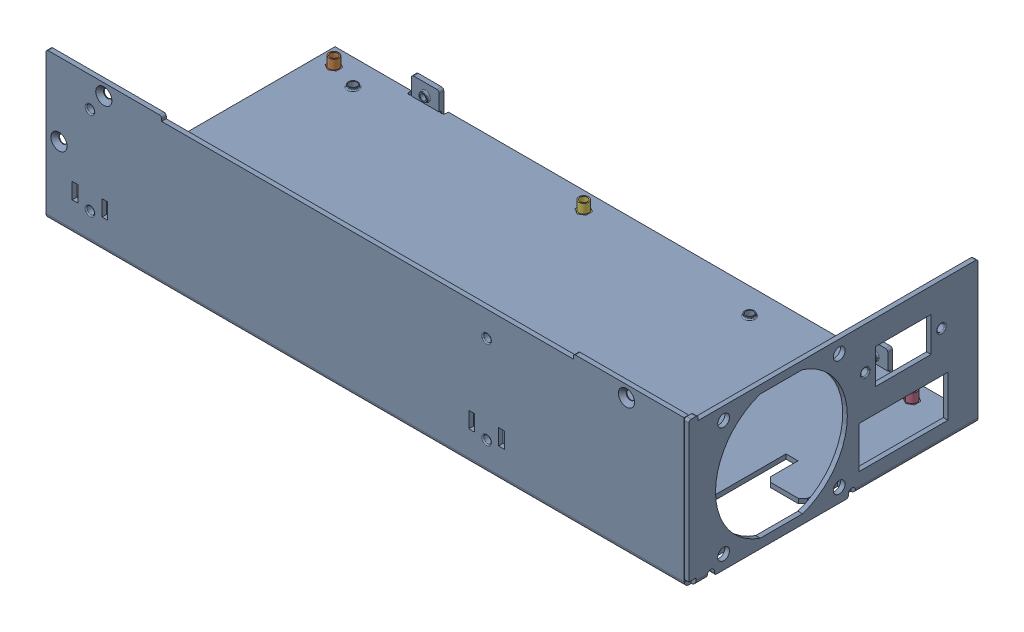
SolidWorks assembly 935B-D, configuration Default. Lengths in mm.
Overall size (278 63.5 125).
6 component instances, 6 part files, 0 mates.
Components (placement in the parent):
- 935B-D-0-1: 935B-D-0 [Default] at origin size (278 63.5 125)
- 3x6 NUT-1: 3x6 NUT [Default] at (-8.5455 -6.0422 -118.9509) x (1 0 0) z (0 -1 0) size (4.8 5.54 6)
- 3x6 NUT_CPY-1: 3x6 NUT_CPY [Default] at (-8.5455 -6.0422 -8.9509) x (1 0 0) z (0 -1 0) size (4.8 5.54 6)
- 3x6 NUT_CPY1-1: 3x6 NUT_CPY1 [Default] at (241.4545 -6.0422 -118.9509) x (1 0 0) z (0 -1 0) size (4.8 5.54 6)
- 3x6 NUT_CPY2-1: 3x6 NUT_CPY2 [Default] at (229.9545 -6.0422 -8.9509) x (1 0 0) z (0 -1 0) size (4.8 5.54 6)
- 3x6 NUT_CPY3-1: 3x6 NUT_CPY3 [Default] at (99.4545 -6.0422 -118.9509) x (1 0 0) z (0 -1 0) size (4.8 5.54 6)
